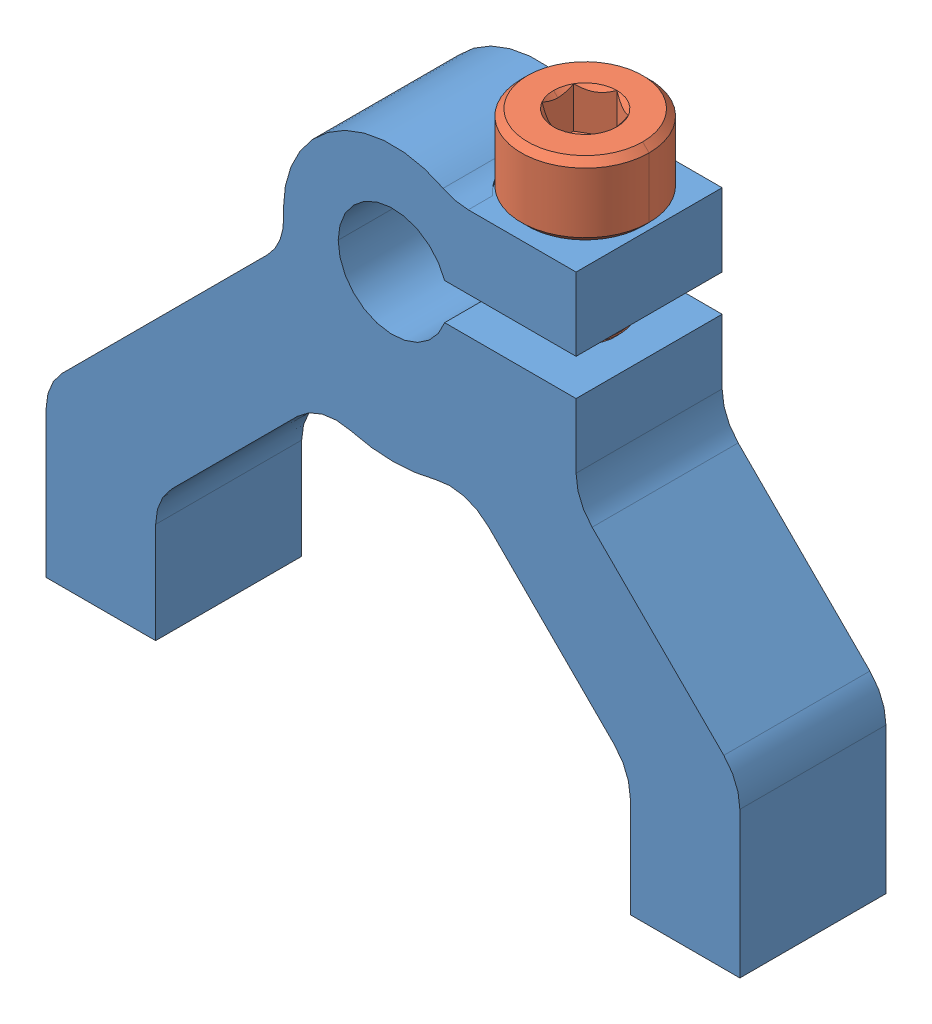
SolidWorks assembly 1-Side, 2-Post Clamping Mount (6mm Bore)1400-0032-0006, configuration Default. Lengths in mm.
Overall size (38 33.01 8).
2 component instances, 2 part files, 0 mates.
Components (placement in the parent):
- 1400-0032-0006.STEP-1: 1400-0032-0006.STEP [Default] at (-10.4545 5.2733 4.1329) size (38 30 8)
- 2800-0004-0010_90128A207.STEP-1: 2800-0004-0010_90128A207.STEP [Default] at (-3.9261 0.2733 8.1329) x (1 0 0) z (0 -1 0) size (7 7 14.01)
